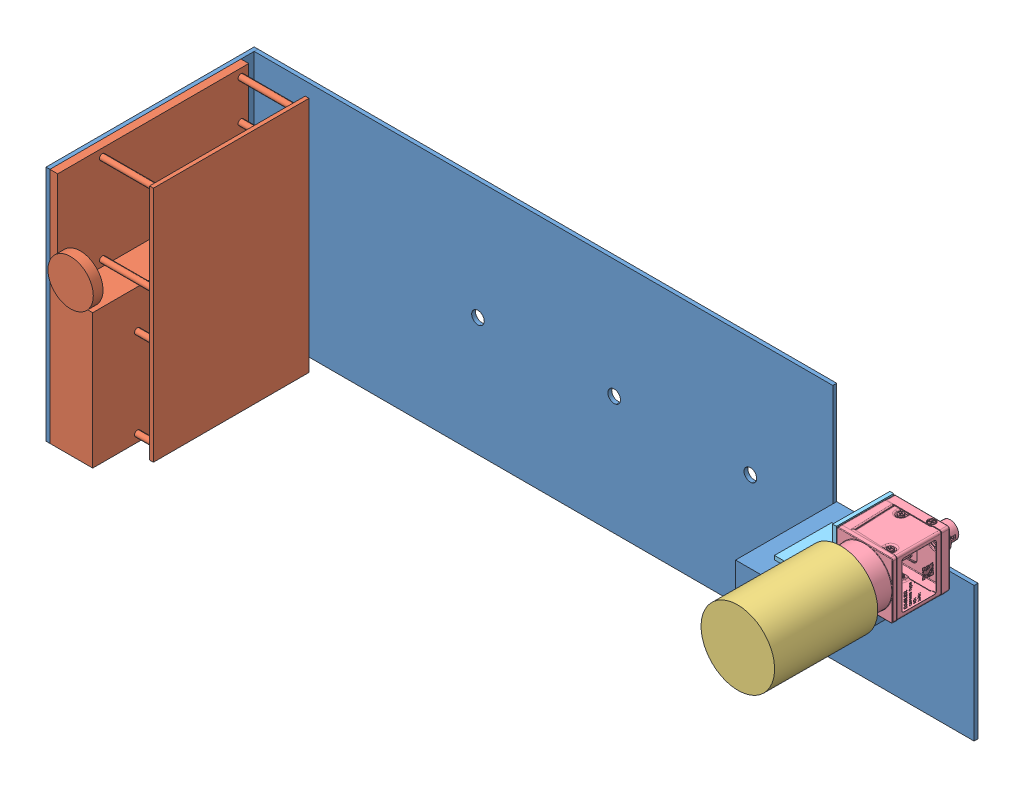
SolidWorks assembly 相机装配SLDASM, configuration 默认. Lengths in mm.
Overall size (382.24 122 112).
5 component instances, 5 part files, 12 mates.
Components (placement in the parent):
- 相机固定架-1: 相机固定架 [默认] at (-1.4723 -5.6313 318.5) size (372 122 107)
- PCB版底座-1: PCB版底座 [默认] at (-153.4723 -5.6313 367.3) x (0 -1 0) z (1 0 0) size (122 103.2 35)
- 镜头-1: 镜头 [默认] at (167.0087 19.1687 425.4143) x (0.576719 0.816937 0.003027) z (0.005249 0 -0.999986) size (38 38 52.75)
- Baslercamera-1: Baslercamera [默认] at (167.2856 19.1687 372.665) x (0 1 0) z (0.005249 0 -0.999986) size (29.17 29.07 48.29)
- fixbracket-1: fixbracket [默认] at (152.9257 19.1687 345.9392) x (0.005249 0 -0.999986) z (-0.999986 0 -0.005249) size (29.3 31 32)
Mates (geometry in assembly coordinates):
- 重合1: coincident anti-aligned: plane of 相机固定架-1 through (-186.4723 55.3687 318.5) normal (1 0 0); plane of PCB版底座-1 through (-186.4723 -5.6313 367.3) normal (-1 0 0)
- 平行1: parallel aligned: plane of 相机固定架-1 through (-186.4723 55.3687 318.5) normal (0 1 0); plane of PCB版底座-1 through (-186.4723 55.3687 327.3) normal (0 1 0)
- 重合2: coincident aligned: plane of 相机固定架-1 through (-1.4723 -5.6313 425.5) normal (0 0 1); plane of PCB版底座-1 through (-186.4723 -66.6313 425.5) normal (0 0 1)
- 重合3: coincident aligned: plane of 相机固定架-1 through (-186.4723 -66.6313 318.5) normal (0 -1 0); plane of PCB版底座-1 through (-186.4723 -66.6313 327.3) normal (0 -1 0)
- 同心1: concentric aligned: cylinder of 镜头-1 through (167.2856 19.1687 372.665) axis (-0.005249 0 0.999986) radius 19; cone of Baslercamera-1 through (167.3484 19.1687 360.6974) axis (-0.005249 0 0.999986)
- 重合4: coincident anti-aligned: plane of 镜头-1 through (167.2856 19.1687 372.665) normal (0.005249 0 -0.999986); plane of Baslercamera-1 through (167.2856 19.1687 372.665) normal (-0.005249 0 0.999986)
- 重合5: coincident anti-aligned: plane of Baslercamera-1 through (152.8488 4.7237 360.589) normal (-0.999986 0 -0.005249); plane of fixbracket-1 through (152.9257 19.1687 345.9392) normal (0.999986 0 0.005249)
- 平行2: parallel aligned: plane of Baslercamera-1 through (157.8879 33.6687 358.5155) normal (0 1 0); plane of fixbracket-1 through (150.8488 33.6687 360.5785) normal (0 1 0)
- 平行3: parallel aligned: plane of Baslercamera-1 through (167.4908 19.1687 331.3655) normal (0.005249 0 -0.999986); plane of fixbracket-1 through (151.0026 4.6687 331.2789) normal (0.005249 0 -0.999986)
- 同心2: concentric anti-aligned: cylinder of Baslercamera-1 through (154.3645 9.1687 357.5969) axis (0.999986 0 0.005249) radius 1.2293; cylinder of fixbracket-1 through (152.8645 9.1687 357.5891) axis (-0.999986 0 -0.005249) radius 1.75
- 同心4: concentric aligned: cylinder of 相机固定架-1 through (135.9277 2.6687 345.5) axis (0 1 0) radius 2.5; cylinder of fixbracket-1 through (135.9277 -25.3313 345.5) axis (0 1 0) radius 3.25
- 重合8: coincident anti-aligned: plane of 相机固定架-1 through (110.9277 2.6687 370.5) normal (0 1 0); plane of fixbracket-1 through (152.8488 2.6687 360.589) normal (0 -1 0)
